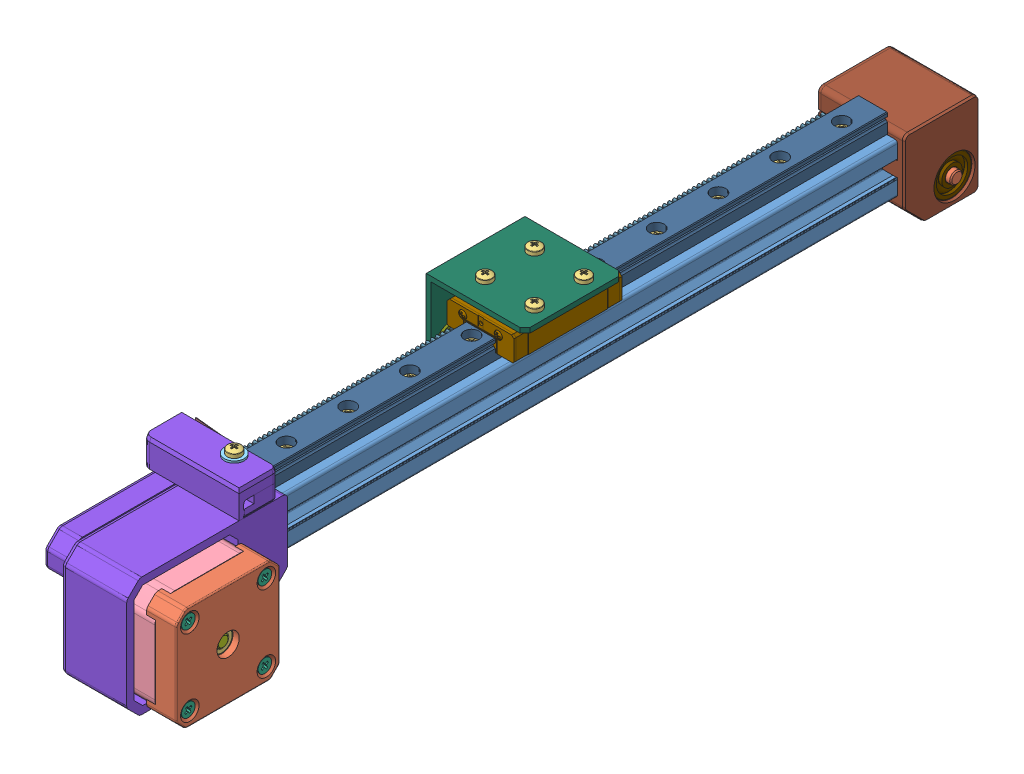
SolidWorks assembly Assem1, configuration По умолчанию. Lengths in mm.
Overall size (62 62.65 345.25).
71 component instances, 24 part files, 140 mates.
Components (placement in the parent):
- rsi_2020_274-1: rsi_2020_274 [По умолчанию] at origin size (20 20 274)
- 17HM15-0904S-1: 17HM15-0904S [По умолчанию] at (30 -11.15 303.15) x (0 0 -1) z (0 1 0) size (42.3 62 42.3)
  - nema17_bottom_40mm-1: nema17_bottom_40mm [По умолчанию] at origin size (42 12 42)
  - radial ball bearing_68_din-1: radial ball bearing_68_din [DIN 625 - 625 - 8,SI,NC,8_68] at (0 5 0) x (0 -1 0) z (0 0 1) size (5 16 16)
  - nema17_middle_40mm-1: nema17_middle_40mm [По умолчанию] at (0 8.5 0) size (42.3 23.5 42.3)
  - nema17_top_40mm-1: nema17_top_40mm [По умолчанию] at (0 32 0) size (42.3 12.6 42.3)
  - radial ball bearing_68_din-3: radial ball bearing_68_din [DIN 625 - 625 - 8,SI,NC,8_68] at (0 38.1 0) x (0 1 0) z (0 0 1) size (5 16 16)
  - countersunk flat head cross recess screw_din-1: countersunk flat head cross recess screw_din [ISO 7046-1 - M3 x 30 - Z --- 30N] at (15.5 0.6 15.5) x (0 1 0) z (0.546944 0 -0.837169) size (30 5.5 5.5)
  - countersunk flat head cross recess screw_din-2: countersunk flat head cross recess screw_din [ISO 7046-1 - M3 x 25 - Z --- 25N] at (15.5 0.6 -15.5) x (0 1 0) z (0.546944 0 -0.837169) size (25 5.5 5.5)
  - countersunk flat head cross recess screw_din-3: countersunk flat head cross recess screw_din [ISO 7046-1 - M3 x 30 - Z --- 30N] at (-15.5 0.6 15.5) x (0 1 0) z (0.546944 0 -0.837169) size (30 5.5 5.5)
  - countersunk flat head cross recess screw_din-4: countersunk flat head cross recess screw_din [ISO 7046-1 - M3 x 30 - Z --- 30N] at (-15.5 0.6 -15.5) x (0 1 0) z (0.546944 0 -0.837169) size (30 5.5 5.5)
  - nema17_shaft_40mm-1: nema17_shaft_40mm [По умолчанию] at (0 2 0) x (-0.412738 0 0.91085) z (-0.91085 0 -0.412738) size (5 60 5)
- nema17_mount_1-1: nema17_mount_1 [По умолчанию] at (-13 -10.7443 294.7873) x (0 0 -1) z (1 0 0) size (65.25 59.3 39.22)
- MGN12-H-1: MGN12-H [По умолчанию] at (0 18 148.9835) size (27 10 45.19)
- MGN12_250-1: MGN12_250 [По умолчанию] at (0 14 12) size (12 8 250)
- idle_pul_mount_1-1: idle_pul_mount_1 [По умолчанию] at (13 -3.403 -4.0666) x (0 0 1) z (-1 0 0) size (30 34 35)
- GT2_16T_13x14-1: GT2_16T_13x14 [Конфигурация1] at (-26.5 -11.15 303.15) x (1 0 0) z (0 0.386253 0.922393) size (14.1 13 13)
- GT2_16T_13x14-2: GT2_16T_13x14 [Конфигурация1] at (-26.5 -11.15 -8.1562) x (1 0 0) z (0 0.133178 -0.991092) size (14.1 13 13)
- SS-5GL_microswitch-2: SS-5GL_microswitch [Default] at (-42.2883 22.25 275.1397) x (0 -1 0) z (1 0 0) size (6.5 17.14 19.7)
- belt_250-1: belt_250 [По умолчанию] at (-19.83 -1.6143 147.7424) size (6 22.27 322.67)
- alum_40x40x2-1: alum_40x40x2 [По умолчанию] at (-21.9 23 168.9835) x (0 0 -1) z (0 -1 0) size (40 40 40)
- idle_pulley_16-1: idle_pulley_16 [По умолчанию] at (-16.4162 -0.75 136.4835) x (0 1 0) z (0 0 1) size (13 9 13)
- idle_pulley_16-2: idle_pulley_16 [По умолчанию] at (-16.4162 -0.75 161.4835) x (0 1 0) z (0 0 1) size (13 9 13)
- mgn12_fix-1: mgn12_fix [По умолчанию] at (0 12.9786 54.5) x (1 0 0) z (0 1 0) size (9.5 35 6)
- mgn12_fix-2: mgn12_fix [По умолчанию] at (0 12.9786 104.5) x (1 0 0) z (0 1 0) size (9.5 35 6)
- mgn12_fix-3: mgn12_fix [По умолчанию] at (0 12.9786 254.5) x (1 0 0) z (0 1 0) size (9.5 35 6)
- mgn12_fix-4: mgn12_fix [По умолчанию] at (0 12.9786 154.5) x (1 0 0) z (0 1 0) size (9.5 35 6)
- mgn12_fix-5: mgn12_fix [По умолчанию] at (0 12.9786 204.5) x (1 0 0) z (0 1 0) size (9.5 35 6)
- instrument ball bearing_68_am-1: instrument ball bearing_68_am [AFBMA 12.1.4.1 - 0050-16 - 8,SI,NC,8_68] at (-9.5 -11.15 -8.1562) size (5 16 16)
- instrument ball bearing_68_am-2: instrument ball bearing_68_am [AFBMA 12.1.4.1 - 0050-16 - 8,SI,NC,8_68] at (9.5 -11.15 -8.1562) size (5 16 16)
- socket head cap screw_am-1: socket head cap screw_am [B18.3.1M - 5 x 0.8 x 20 Hex SHCS -- 20NHX] at (0 0 280.85) x (0 0 -1) z (1 0 0) size (25 8.5 8.5)
- socket head cap screw_am-2: socket head cap screw_am [B18.3.1M - 5 x 0.8 x 20 Hex SHCS -- 20NHX] at (0 0 -11) x (0 0 1) z (-1 0 0) size (25 8.5 8.5)
- continous stud_am-1: continous stud_am [AM -- M5 x 45  N] at (-31 -11.15 -8.1562) size (45 5 5)
- pan head cross recess screw_din-1: pan head cross recess screw_din [ISO 7045 - M3 x 16 - Z --- 16N] at (-10 -0.75 161.4835) x (-1 0 0) z (0 0.924225 0.381849) size (18.35 5.6 5.6)
- pan head cross recess screw_din-2: pan head cross recess screw_din [ISO 7045 - M3 x 16 - Z --- 16N] at (-10 -0.75 136.4835) x (-1 0 0) z (0 0.924225 0.381849) size (18.35 5.6 5.6)
- prevailing torque nut style 1 insert_din-3: prevailing torque nut style 1 insert_din [DIN EN ISO 7040 - M3 - N] at (-26.05 -0.75 136.4835) x (0 0 1) z (-1 0 0) size (5.5 6.35 4.5)
- prevailing torque nut style 1 insert_din-4: prevailing torque nut style 1 insert_din [DIN EN ISO 7040 - M3 - N] at (-26.05 -0.75 161.4835) x (0 0 1) z (-1 0 0) size (5.5 6.35 4.5)
- plain washer 6902 type abc_din-1: plain washer 6902 type abc_din [DIN 6902-A3.2] at (-13 -26.65 318.65) x (-1 0 0) z (0 0.924225 0.381849) size (0.8 8 8)
- pan head cross recess screw_din-4: pan head cross recess screw_din [ISO 7045 - M3 x 6 - Z --- 6N] at (-16.2 -26.65 318.65) size (8.35 5.6 5.6)
- pan head cross recess screw_din-5: pan head cross recess screw_din [ISO 7045 - M3 x 6 - Z --- 6N] at (-16.2 -26.65 287.65) size (8.35 5.6 5.6)
- plain washer 6902 type abc_din-2: plain washer 6902 type abc_din [DIN 6902-A3.2] at (-13 -26.65 287.65) x (-1 0 0) z (0 0.924225 0.381849) size (0.8 8 8)
- pan head cross recess screw_din-6: pan head cross recess screw_din [ISO 7045 - M3 x 16 - Z --- 16N] at (-25.2 4.35 287.65) size (18.35 5.6 5.6)
- plain washer 6902 type abc_din-3: plain washer 6902 type abc_din [DIN 6902-A3.2] at (-22 4.35 287.65) x (-1 0 0) z (0 0.924225 0.381849) size (0.8 8 8)
- plain washer 6902 type abc_din-4: plain washer 6902 type abc_din [DIN 6902-A3.2] at (-22 4.35 318.65) x (-1 0 0) z (0 0.924225 0.381849) size (0.8 8 8)
- pan head cross recess screw_din-7: pan head cross recess screw_din [ISO 7045 - M3 x 20 - Z --- 20N] at (-25.2 4.35 318.65) size (22.35 5.6 5.6)
- pan head cross recess screw_din-9: pan head cross recess screw_din [ISO 7045 - M3 x 8 - Z --- 8N] at (0 15.9 24.5) x (0 -1 0) z (0 0 1) size (10.35 5.6 5.6)
- pan head cross recess screw_din-10: pan head cross recess screw_din [ISO 7045 - M3 x 8 - Z --- 8N] at (0 15.9 49.5) x (0 -1 0) z (-0.931961 0 -0.362559) size (10.35 5.6 5.6)
- hex nut style 1 gradeab_din-1: hex nut style 1 gradeab_din [Hexagon Nut ISO 4032 - M3 - D - N] at (0 5.1 24.5) x (0.5 0 0.866025) z (0 -1 0) size (5.5 6.35 2.4)
- hex nut style 1 gradeab_din-2: hex nut style 1 gradeab_din [Hexagon Nut ISO 4032 - M3 - D - N] at (0 5.1 49.5) x (0.5 0 0.866025) z (0 -1 0) size (5.5 6.35 2.4)
- hex nut style 1 gradeab_din-3: hex nut style 1 gradeab_din [Hexagon Nut ISO 4032 - M3 - D - N] at (0 5.1 99.5) x (0.5 0 0.866025) z (0 -1 0) size (5.5 6.35 2.4)
- hex nut style 1 gradeab_din-4: hex nut style 1 gradeab_din [Hexagon Nut ISO 4032 - M3 - D - N] at (0 5.1 74.5) x (0.5 0 0.866025) z (0 -1 0) size (5.5 6.35 2.4)
- pan head cross recess screw_din-11: pan head cross recess screw_din [ISO 7045 - M3 x 8 - Z --- 8N] at (0 15.9 74.5) x (0 -1 0) z (0 0 1) size (10.35 5.6 5.6)
- pan head cross recess screw_din-12: pan head cross recess screw_din [ISO 7045 - M3 x 8 - Z --- 8N] at (0 15.9 99.5) x (0 -1 0) z (-0.931961 0 -0.362559) size (10.35 5.6 5.6)
- hex nut style 1 gradeab_din-5: hex nut style 1 gradeab_din [Hexagon Nut ISO 4032 - M3 - D - N] at (0 5.1 249.5) x (0.5 0 0.866025) z (0 -1 0) size (5.5 6.35 2.4)
- hex nut style 1 gradeab_din-6: hex nut style 1 gradeab_din [Hexagon Nut ISO 4032 - M3 - D - N] at (0 5.1 224.5) x (0.5 0 0.866025) z (0 -1 0) size (5.5 6.35 2.4)
- pan head cross recess screw_din-13: pan head cross recess screw_din [ISO 7045 - M3 x 8 - Z --- 8N] at (0 15.9 224.5) x (0 -1 0) z (0 0 1) size (10.35 5.6 5.6)
- pan head cross recess screw_din-14: pan head cross recess screw_din [ISO 7045 - M3 x 8 - Z --- 8N] at (0 15.9 249.5) x (0 -1 0) z (-0.931961 0 -0.362559) size (10.35 5.6 5.6)
- hex nut style 1 gradeab_din-7: hex nut style 1 gradeab_din [Hexagon Nut ISO 4032 - M3 - D - N] at (0 5.1 149.5) x (0.5 0 0.866025) z (0 -1 0) size (5.5 6.35 2.4)
- hex nut style 1 gradeab_din-8: hex nut style 1 gradeab_din [Hexagon Nut ISO 4032 - M3 - D - N] at (0 5.1 124.5) x (0.5 0 0.866025) z (0 -1 0) size (5.5 6.35 2.4)
- pan head cross recess screw_din-15: pan head cross recess screw_din [ISO 7045 - M3 x 8 - Z --- 8N] at (0 15.9 124.5) x (0 -1 0) z (0 0 1) size (10.35 5.6 5.6)
- pan head cross recess screw_din-16: pan head cross recess screw_din [ISO 7045 - M3 x 8 - Z --- 8N] at (0 15.9 149.5) x (0 -1 0) z (-0.931961 0 -0.362559) size (10.35 5.6 5.6)
- hex nut style 1 gradeab_din-9: hex nut style 1 gradeab_din [Hexagon Nut ISO 4032 - M3 - D - N] at (0 5.1 199.5) x (0.5 0 0.866025) z (0 -1 0) size (5.5 6.35 2.4)
- hex nut style 1 gradeab_din-10: hex nut style 1 gradeab_din [Hexagon Nut ISO 4032 - M3 - D - N] at (0 5.1 174.5) x (0.5 0 0.866025) z (0 -1 0) size (5.5 6.35 2.4)
- pan head cross recess screw_din-17: pan head cross recess screw_din [ISO 7045 - M3 x 8 - Z --- 8N] at (0 15.9 174.5) x (0 -1 0) z (0 0 1) size (10.35 5.6 5.6)
- pan head cross recess screw_din-18: pan head cross recess screw_din [ISO 7045 - M3 x 8 - Z --- 8N] at (0 15.9 199.5) x (0 -1 0) z (-0.931961 0 -0.362559) size (10.35 5.6 5.6)
- pan head cross recess screw_din-19: pan head cross recess screw_din [ISO 7045 - M3 x 6 - Z --- 6N] at (-10 27.4 158.9835) x (0 -1 0) z (0 0 1) size (8.35 5.6 5.6)
- pan head cross recess screw_din-20: pan head cross recess screw_din [ISO 7045 - M3 x 6 - Z --- 6N] at (-10 27.4 138.9835) x (0 -1 0) z (0 0 1) size (8.35 5.6 5.6)
- pan head cross recess screw_din-21: pan head cross recess screw_din [ISO 7045 - M3 x 6 - Z --- 6N] at (10 27.4 138.9835) x (0 -1 0) z (0 0 1) size (8.35 5.6 5.6)
- pan head cross recess screw_din-22: pan head cross recess screw_din [ISO 7045 - M3 x 6 - Z --- 6N] at (10 27.4 158.9835) x (0 -1 0) z (0 0 1) size (8.35 5.6 5.6)
- plain washer 6902 type abc_din-5: plain washer 6902 type abc_din [DIN 6902-A3.2] at (0 24 270.6521) x (0 1 0) z (0.924225 0 0.381849) size (0.8 8 8)
- pan head cross recess screw_din-23: pan head cross recess screw_din [ISO 7045 - M3 x 16 - Z --- 16N] at (0 27.2 270.6521) x (0 -1 0) z (0 0 1) size (18.35 5.6 5.6)
Mates (geometry in assembly coordinates):
- Concentric1: concentric aligned: cylinder of rsi_2020_274-1 through (0 0 274) axis (0 0 -1) radius 2.5; cylinder of nema17_mount_1-1 through (0 0 327.251) axis (0 0 -1) radius 3.1
- Coincident4: coincident anti-aligned: plane of rsi_2020_274-1 through (0 0 274) normal (0 0 1); plane of nema17_mount_1-1 through (-13 -10.7443 274) normal (0 0 -1)
- Parallel2: parallel aligned: plane of rsi_2020_274-1 through (10 0 274) normal (1 0 0); plane of nema17_mount_1-1 through (13 -10.7443 294.7873) normal (1 0 0)
- Concentric2: concentric anti-aligned: cylinder of 17HM15-0904S-1/nema17_top_40mm-1 through (-12 -11.15 303.15) axis (1 0 0) radius 11; cylinder of nema17_mount_1-1 through (-10 -11.15 303.15) axis (-1 0 0) radius 11.05
- Coincident6: coincident anti-aligned: plane of 17HM15-0904S-1/nema17_top_40mm-1 through (-10 -11.15 303.15) normal (-1 0 0); plane of nema17_mount_1-1 through (-10 -10.7443 294.7873) normal (1 0 0)
- Parallel3: parallel aligned: plane of 17HM15-0904S-1/nema17_middle_40mm-1 through (-2 10 317.5735) normal (0 1 0); plane of nema17_mount_1-1 through (13 13 294.7873) normal (0 1 0)
- Coincident8: coincident anti-aligned: plane of MGN12-H-1 through (6 18 165.1835) normal (-1 0 0); plane of MGN12_250-1 through (6 10.3 262) normal (1 0 0)
- Coincident9: coincident anti-aligned: plane of MGN12-H-1 through (0 18 165.1835) normal (0 -1 0); plane of MGN12_250-1 through (-5.7 18 262) normal (0 1 0)
- Coincident10: coincident anti-aligned: plane of rsi_2020_274-1 through (0 10 274) normal (0 1 0); plane of MGN12_250-1 through (-5.7 10 262) normal (0 -1 0)
- Coincident11: coincident anti-aligned: plane of nema17_mount_1-1 through (13 -10.7443 262) normal (0 0 -1); plane of MGN12_250-1 through (6.3091 15.5 262) normal (0 0 1)
- Distance2: distance = 4 mm aligned: plane of MGN12_250-1 through (-6 10.3 262) normal (-1 0 0); plane of rsi_2020_274-1 through (-10 0 274) normal (-1 0 0)
- Concentric5: concentric anti-aligned: cylinder of rsi_2020_274-1 through (0 0 274) axis (0 0 -1) radius 2.5; cylinder of idle_pul_mount_1-1 through (0 0 -18.001) axis (0 0 1) radius 3.1
- Coincident14: coincident anti-aligned: plane of rsi_2020_274-1 through (0 0 0) normal (0 0 -1); plane of idle_pul_mount_1-1 through (13 -3.403 0) normal (0 0 1)
- Concentric6: concentric aligned: cylinder of 17HM15-0904S-1/nema17_shaft_40mm-1 through (-32 -11.15 303.15) axis (1 0 0) radius 2.5; cylinder of GT2_16T_13x14-1 through (-26.5 -11.15 303.15) axis (1 0 0) radius 2.5
- Coincident15: coincident anti-aligned: plane of idle_pul_mount_1-1 through (-7 -11.15 -8.1562) normal (-1 0 0); plane of instrument ball bearing_68_am-1 through (-7 -3.45 -8.1562) normal (1 0 0)
- Concentric7: concentric anti-aligned: cylinder of idle_pul_mount_1-1 through (-7 -11.15 -8.1562) axis (-1 0 0) radius 8; cylinder of instrument ball bearing_68_am-1 through (-30.1375 -11.15 -8.1562) axis (1 0 0) radius 8
- Coincident16: coincident aligned: circle of idle_pul_mount_1-1; plane of instrument ball bearing_68_am-2 through (7 -4.8 -8.1562) normal (-1 0 0)
- Concentric8: concentric aligned: cylinder of idle_pul_mount_1-1 through (7 -11.15 -8.1562) axis (1 0 0) radius 8; cylinder of instrument ball bearing_68_am-2 through (-11.1375 -11.15 -8.1562) axis (1 0 0) radius 8
- Concentric9: concentric anti-aligned: cylinder of idle_pul_mount_1-1 through (0 0 -18.001) axis (0 0 1) radius 3.1; cylinder of socket head cap screw_am-2 through (0 0 -42.75) axis (0 0 -1) radius 4.25
- Coincident17: coincident anti-aligned: plane of idle_pul_mount_1-1 through (0 0 -6) normal (0 0 -1); plane of socket head cap screw_am-2 through (0 4.25 -6) normal (0 0 1)
- Concentric10: concentric anti-aligned: cylinder of nema17_mount_1-1 through (0 0 327.251) axis (0 0 -1) radius 3.1; cylinder of socket head cap screw_am-1 through (0 0 312.6) axis (0 0 1) radius 2.5
- Coincident18: coincident anti-aligned: plane of nema17_mount_1-1 through (0 0 275.85) normal (0 0 1); plane of socket head cap screw_am-1 through (0 4.25 275.85) normal (0 0 -1)
- Concentric11: concentric anti-aligned: cylinder of instrument ball bearing_68_am-1 through (-30.1375 -11.15 -8.1562) axis (1 0 0) radius 2.5; cylinder of continous stud_am-1 through (-34.175 -11.15 -8.1562) axis (-1 0 0) radius 2.5
- Distance3: distance = 2 mm aligned: plane of continous stud_am-1 through (14 -8.65 -8.1562) normal (1 0 0); plane of instrument ball bearing_68_am-2 through (12 -8.35 -8.1562) normal (1 0 0)
- Concentric12: concentric anti-aligned: cylinder of continous stud_am-1 through (-34.175 -11.15 -8.1562) axis (-1 0 0) radius 2.5; cylinder of GT2_16T_13x14-2 through (-26.5 -11.15 -8.1562) axis (1 0 0) radius 2.5
- Coincident20: coincident aligned: plane of nema17_mount_1-1 through (13 13 294.7873) normal (0 1 0); plane of idle_pul_mount_1-1 through (-13 13 -4.0666) normal (0 1 0)
- Coincident21: coincident aligned: plane of GT2_16T_13x14-1 through (-26.5 -11.15 303.15) normal (-1 0 0); plane of GT2_16T_13x14-2 through (-26.5 -11.15 -8.1562) normal (-1 0 0)
- Distance4: distance = 0.5 mm anti-aligned: plane of GT2_16T_13x14-2 through (-20.33 -11.15 -8.1562) normal (1 0 0); plane of belt_250-1 through (-19.83 -5.8558 5.1368) normal (-1 0 0)
- Coincident23: coincident anti-aligned: plane of MGN12-H-1 through (0 23 165.1835) normal (0 1 0); plane of alum_40x40x2-1 through (-21.9 23 128.9835) normal (0 -1 0)
- Concentric13: concentric anti-aligned: cylinder of alum_40x40x2-1 through (16.101 -0.75 136.4835) axis (-1 0 0) radius 1.5; cylinder of idle_pulley_16-1 through (-16.4162 -0.75 136.4835) axis (1 0 0) radius 1.5
- Concentric14: concentric anti-aligned: cylinder of alum_40x40x2-1 through (16.101 -0.75 161.4835) axis (-1 0 0) radius 1.5; cylinder of idle_pulley_16-2 through (-16.4162 -0.75 161.4835) axis (1 0 0) radius 1.5
- Distance6: distance = 0.5 mm anti-aligned: plane of idle_pulley_16-1 through (-21.4 -0.75 134.9835) normal (-1 0 0); plane of alum_40x40x2-1 through (-21.9 -15 128.9835) normal (1 0 0)
- Distance7: distance = 0.5 mm anti-aligned: plane of idle_pulley_16-2 through (-21.4 -0.75 159.9835) normal (-1 0 0); plane of alum_40x40x2-1 through (-21.9 -15 128.9835) normal (1 0 0)
- Concentric15: concentric aligned: cylinder of idle_pulley_16-2 through (-16.4162 -0.75 161.4835) axis (1 0 0) radius 1.5; cylinder of pan head cross recess screw_din-1 through (15.4 -0.75 161.4835) axis (1 0 0) radius 2.8
- Coincident28: coincident anti-aligned: plane of idle_pulley_16-2 through (-12.4 -0.75 154.9835) normal (1 0 0); plane of pan head cross recess screw_din-1 through (-12.4 -1.3228 162.8699) normal (-1 0 0)
- Concentric16: concentric aligned: cylinder of idle_pulley_16-1 through (-16.4162 -0.75 136.4835) axis (1 0 0) radius 1.5; cylinder of pan head cross recess screw_din-2 through (15.4 -0.75 136.4835) axis (1 0 0) radius 2.8
- Coincident29: coincident anti-aligned: plane of idle_pulley_16-1 through (-12.4 -0.75 129.9835) normal (1 0 0); plane of pan head cross recess screw_din-2 through (-12.4 -1.3228 137.8699) normal (-1 0 0)
- Concentric20: concentric aligned: cylinder of MGN12-H-1 through (-10 17.15 158.9835) axis (0 1 0) radius 1.5; cylinder of alum_40x40x2-1 through (-10 -15.001 158.9835) axis (0 1 0) radius 1.5
- Concentric21: concentric aligned: cylinder of MGN12-H-1 through (10 17.15 138.9835) axis (0 1 0) radius 1.5; cylinder of alum_40x40x2-1 through (10 -15.001 138.9835) axis (0 1 0) radius 1.5
- Concentric29: concentric anti-aligned: cylinder of pan head cross recess screw_din-2 through (15.4 -0.75 136.4835) axis (1 0 0) radius 1.5; cylinder of prevailing torque nut style 1 insert_din-3 through (-23.9 -0.75 136.4835) axis (-1 0 0) radius 1.25
- Concentric30: concentric anti-aligned: cylinder of pan head cross recess screw_din-1 through (15.4 -0.75 161.4835) axis (1 0 0) radius 1.5; cylinder of prevailing torque nut style 1 insert_din-4 through (-23.9 -0.75 161.4835) axis (-1 0 0) radius 1.25
- Coincident36: coincident anti-aligned: plane of alum_40x40x2-1 through (-23.9 25 128.9835) normal (-1 0 0); plane of prevailing torque nut style 1 insert_din-3 through (-23.9 -0.75 130.9835) normal (1 0 0)
- Coincident37: coincident anti-aligned: plane of alum_40x40x2-1 through (-23.9 25 128.9835) normal (-1 0 0); plane of prevailing torque nut style 1 insert_din-4 through (-23.9 -0.75 155.9835) normal (1 0 0)
- Concentric32: concentric anti-aligned: cylinder of nema17_mount_1-1 through (-10 -26.65 318.65) axis (-1 0 0) radius 1.6; cylinder of plain washer 6902 type abc_din-1 through (-13.8 -26.65 318.65) axis (1 0 0) radius 1.6
- Coincident39: coincident anti-aligned: plane of nema17_mount_1-1 through (-13 -10.7443 294.7873) normal (-1 0 0); plane of plain washer 6902 type abc_din-1 through (-13 -26.65 318.65) normal (1 0 0)
- Coincident40: coincident anti-aligned: plane of plain washer 6902 type abc_din-1 through (-13.8 -26.65 318.65) normal (-1 0 0); plane of pan head cross recess screw_din-4 through (-13.8 -25.15 318.65) normal (1 0 0)
- Concentric41: concentric anti-aligned: cylinder of plain washer 6902 type abc_din-1 through (-13.8 -26.65 318.65) axis (1 0 0) radius 1.6; cylinder of pan head cross recess screw_din-4 through (-41.6 -26.65 318.65) axis (-1 0 0) radius 1.5
- Coincident47: coincident anti-aligned: plane of pan head cross recess screw_din-5 through (-13.8 -25.15 287.65) normal (1 0 0); plane of plain washer 6902 type abc_din-2 through (-13.8 -26.65 287.65) normal (-1 0 0)
- Concentric42: concentric anti-aligned: cylinder of pan head cross recess screw_din-5 through (-41.6 -26.65 287.65) axis (-1 0 0) radius 1.5; cylinder of plain washer 6902 type abc_din-2 through (-13.8 -26.65 287.65) axis (1 0 0) radius 1.6
- Concentric43: concentric anti-aligned: cylinder of nema17_mount_1-1 through (-10 -26.65 287.65) axis (-1 0 0) radius 1.6; cylinder of plain washer 6902 type abc_din-2 through (-13.8 -26.65 287.65) axis (1 0 0) radius 1.6
- Coincident48: coincident anti-aligned: plane of nema17_mount_1-1 through (-13 -10.7443 294.7873) normal (-1 0 0); plane of plain washer 6902 type abc_din-2 through (-13 -26.65 287.65) normal (1 0 0)
- Coincident49: coincident anti-aligned: plane of pan head cross recess screw_din-6 through (-22.8 5.85 287.65) normal (1 0 0); plane of plain washer 6902 type abc_din-3 through (-22.8 4.35 287.65) normal (-1 0 0)
- Concentric44: concentric anti-aligned: cylinder of pan head cross recess screw_din-6 through (-50.6 4.35 287.65) axis (-1 0 0) radius 1.5; cylinder of plain washer 6902 type abc_din-3 through (-22.8 4.35 287.65) axis (1 0 0) radius 1.6
- Concentric45: concentric anti-aligned: cylinder of nema17_mount_1-1 through (-10 4.35 287.65) axis (-1 0 0) radius 1.6; cylinder of plain washer 6902 type abc_din-3 through (-22.8 4.35 287.65) axis (1 0 0) radius 1.6
- Coincident50: coincident anti-aligned: plane of nema17_mount_1-1 through (-22 2 264) normal (-1 0 0); plane of plain washer 6902 type abc_din-3 through (-22 4.35 287.65) normal (1 0 0)
- Coincident51: coincident anti-aligned: plane of plain washer 6902 type abc_din-4 through (-22.8 4.35 318.65) normal (-1 0 0); plane of pan head cross recess screw_din-7 through (-22.8 5.85 318.65) normal (1 0 0)
- Concentric46: concentric anti-aligned: cylinder of plain washer 6902 type abc_din-4 through (-22.8 4.35 318.65) axis (1 0 0) radius 1.6; cylinder of pan head cross recess screw_din-7 through (-50.6 4.35 318.65) axis (-1 0 0) radius 1.5
- Concentric47: concentric anti-aligned: cylinder of nema17_mount_1-1 through (-10 4.35 318.65) axis (-1 0 0) radius 1.6; cylinder of plain washer 6902 type abc_din-4 through (-22.8 4.35 318.65) axis (1 0 0) radius 1.6
- Coincident52: coincident anti-aligned: plane of nema17_mount_1-1 through (-22 2 264) normal (-1 0 0); plane of plain washer 6902 type abc_din-4 through (-22 4.35 318.65) normal (1 0 0)
- Distance9: distance = 5.5 mm aligned: plane of GT2_16T_13x14-1 through (-26.5 -11.15 303.15) normal (-1 0 0); plane of 17HM15-0904S-1/nema17_shaft_40mm-1 through (-32 -11.15 303.15) normal (-1 0 0)
- Concentric50: concentric anti-aligned: cylinder of MGN12_250-1 through (0 10 24.5) axis (0 1 0) radius 1.75; cylinder of mgn12_fix-1 through (0 10.001 24.5) axis (0 -1 0) radius 1.6
- Concentric51: concentric anti-aligned: cylinder of MGN12_250-1 through (0 10 49.5) axis (0 1 0) radius 1.75; cylinder of mgn12_fix-1 through (0 10.001 49.5) axis (0 -1 0) radius 1.6
- Coincident55: coincident anti-aligned: plane of MGN12_250-1 through (-5.7 10 262) normal (0 -1 0); plane of mgn12_fix-1 through (-3 10 19.5) normal (0 1 0)
- Concentric54: concentric aligned: cylinder of MGN12_250-1 through (0 10 49.5) axis (0 1 0) radius 1.75; cylinder of pan head cross recess screw_din-10 through (0 41.3 49.5) axis (0 1 0) radius 2.8
- Coincident57: coincident anti-aligned: plane of MGN12_250-1 through (0 13.5 49.5) normal (0 1 0); plane of pan head cross recess screw_din-10 through (-0.5438 13.5 50.8979) normal (0 -1 0)
- Parallel6: parallel aligned: plane of mgn12_fix-1 through (-2.9 7.5 22.8257) normal (0.5 0 0.866025); plane of hex nut style 1 gradeab_din-1 through (0 7.5 27.6754) normal (0.5 0 0.866025)
- Coincident61: coincident anti-aligned: plane of mgn12_fix-1 through (0 7.5 54.5) normal (0 -1 0); plane of hex nut style 1 gradeab_din-1 through (-2.75 7.5 26.0877) normal (0 1 0)
- Concentric57: concentric anti-aligned: cylinder of pan head cross recess screw_din-10 through (0 41.3 49.5) axis (0 1 0) radius 1.5; cylinder of hex nut style 1 gradeab_din-2 through (0 7.5 49.5) axis (0 -1 0) radius 1.25
- Parallel7: parallel aligned: plane of mgn12_fix-1 through (0 7.5 46.1514) normal (0.5 0 0.866025); plane of hex nut style 1 gradeab_din-2 through (0 7.5 52.6754) normal (0.5 0 0.866025)
- Coincident62: coincident anti-aligned: plane of mgn12_fix-1 through (0 7.5 54.5) normal (0 -1 0); plane of hex nut style 1 gradeab_din-2 through (-2.75 7.5 51.0877) normal (0 1 0)
- Concentric59: concentric aligned: cylinder of MGN12_250-1 through (0 10 24.5) axis (0 1 0) radius 1.75; cylinder of pan head cross recess screw_din-9 through (0 41.3 24.5) axis (0 1 0) radius 1.5
- Coincident64: coincident anti-aligned: plane of MGN12_250-1 through (0 13.5 24.5) normal (0 1 0); plane of pan head cross recess screw_din-9 through (1.5 13.5 24.5) normal (0 -1 0)
- Concentric85: concentric anti-aligned: cylinder of pan head cross recess screw_din-9 through (0 41.3 24.5) axis (0 1 0) radius 1.5; cylinder of hex nut style 1 gradeab_din-1 through (0 7.5 24.5) axis (0 -1 0) radius 1.25
- Parallel16: parallel aligned: plane of mgn12_fix-2 through (-2.9 7.5 72.8257) normal (0.5 0 0.866025); plane of hex nut style 1 gradeab_din-4 through (0 7.5 77.6754) normal (0.5 0 0.866025)
- Coincident85: coincident anti-aligned: plane of mgn12_fix-2 through (0 7.5 104.5) normal (0 -1 0); plane of hex nut style 1 gradeab_din-4 through (-2.75 7.5 76.0877) normal (0 1 0)
- Concentric86: concentric anti-aligned: cylinder of hex nut style 1 gradeab_din-3 through (0 7.5 99.5) axis (0 -1 0) radius 1.25; cylinder of pan head cross recess screw_din-12 through (0 41.3 99.5) axis (0 1 0) radius 1.5
- Parallel17: parallel aligned: plane of mgn12_fix-2 through (0 7.5 96.1514) normal (0.5 0 0.866025); plane of hex nut style 1 gradeab_din-3 through (0 7.5 102.6754) normal (0.5 0 0.866025)
- Coincident86: coincident anti-aligned: plane of mgn12_fix-2 through (0 7.5 104.5) normal (0 -1 0); plane of hex nut style 1 gradeab_din-3 through (-2.75 7.5 101.0877) normal (0 1 0)
- Concentric87: concentric anti-aligned: cylinder of hex nut style 1 gradeab_din-4 through (0 7.5 74.5) axis (0 -1 0) radius 1.25; cylinder of pan head cross recess screw_din-11 through (0 41.3 74.5) axis (0 1 0) radius 1.5
- Concentric88: concentric anti-aligned: cylinder of MGN12_250-1 through (0 10 74.5) axis (0 1 0) radius 1.75; cylinder of mgn12_fix-2 through (0 10.001 74.5) axis (0 -1 0) radius 1.6
- Concentric89: concentric anti-aligned: cylinder of MGN12_250-1 through (0 10 99.5) axis (0 1 0) radius 1.75; cylinder of mgn12_fix-2 through (0 10.001 99.5) axis (0 -1 0) radius 1.6
- Coincident87: coincident anti-aligned: plane of MGN12_250-1 through (-5.7 10 262) normal (0 -1 0); plane of mgn12_fix-2 through (-3 10 69.5) normal (0 1 0)
- Concentric90: concentric aligned: cylinder of MGN12_250-1 through (0 10 99.5) axis (0 1 0) radius 1.75; cylinder of pan head cross recess screw_din-12 through (0 41.3 99.5) axis (0 1 0) radius 2.8
- Coincident88: coincident anti-aligned: plane of MGN12_250-1 through (0 13.5 49.5) normal (0 1 0); plane of pan head cross recess screw_din-12 through (-0.5438 13.5 100.8979) normal (0 -1 0)
- Concentric91: concentric aligned: cylinder of MGN12_250-1 through (0 10 74.5) axis (0 1 0) radius 1.75; cylinder of pan head cross recess screw_din-11 through (0 41.3 74.5) axis (0 1 0) radius 1.5
- Coincident89: coincident anti-aligned: plane of MGN12_250-1 through (0 13.5 24.5) normal (0 1 0); plane of pan head cross recess screw_din-11 through (1.5 13.5 74.5) normal (0 -1 0)
- Parallel18: parallel aligned: plane of mgn12_fix-3 through (-2.9 7.5 222.8257) normal (0.5 0 0.866025); plane of hex nut style 1 gradeab_din-6 through (0 7.5 227.6754) normal (0.5 0 0.866025)
- Coincident90: coincident anti-aligned: plane of mgn12_fix-3 through (0 7.5 254.5) normal (0 -1 0); plane of hex nut style 1 gradeab_din-6 through (-2.75 7.5 226.0877) normal (0 1 0)
- Concentric92: concentric anti-aligned: cylinder of hex nut style 1 gradeab_din-5 through (0 7.5 249.5) axis (0 -1 0) radius 1.25; cylinder of pan head cross recess screw_din-14 through (0 41.3 249.5) axis (0 1 0) radius 1.5
- Parallel19: parallel aligned: plane of mgn12_fix-3 through (0 7.5 246.1514) normal (0.5 0 0.866025); plane of hex nut style 1 gradeab_din-5 through (0 7.5 252.6754) normal (0.5 0 0.866025)
- Coincident91: coincident anti-aligned: plane of mgn12_fix-3 through (0 7.5 254.5) normal (0 -1 0); plane of hex nut style 1 gradeab_din-5 through (-2.75 7.5 251.0877) normal (0 1 0)
- Concentric93: concentric anti-aligned: cylinder of hex nut style 1 gradeab_din-6 through (0 7.5 224.5) axis (0 -1 0) radius 1.25; cylinder of pan head cross recess screw_din-13 through (0 41.3 224.5) axis (0 1 0) radius 1.5
- Concentric94: concentric anti-aligned: cylinder of MGN12_250-1 through (0 10 224.5) axis (0 1 0) radius 1.75; cylinder of mgn12_fix-3 through (0 10.001 224.5) axis (0 -1 0) radius 1.6
- Coincident92: coincident anti-aligned: plane of MGN12_250-1 through (-5.7 10 262) normal (0 -1 0); plane of mgn12_fix-3 through (-3 10 219.5) normal (0 1 0)
- Coincident93: coincident anti-aligned: plane of MGN12_250-1 through (0 13.5 49.5) normal (0 1 0); plane of pan head cross recess screw_din-14 through (-0.5438 13.5 250.8979) normal (0 -1 0)
- Coincident94: coincident anti-aligned: plane of MGN12_250-1 through (0 13.5 24.5) normal (0 1 0); plane of pan head cross recess screw_din-13 through (1.5 13.5 224.5) normal (0 -1 0)
- Concentric95: concentric anti-aligned: cylinder of MGN12_250-1 through (0 10 249.5) axis (0 1 0) radius 1.75; cylinder of mgn12_fix-3 through (0 10.001 249.5) axis (0 -1 0) radius 1.6
- Concentric96: concentric aligned: cylinder of MGN12_250-1 through (0 10 249.5) axis (0 1 0) radius 1.75; cylinder of pan head cross recess screw_din-14 through (0 41.3 249.5) axis (0 1 0) radius 2.8
- Concentric97: concentric aligned: cylinder of MGN12_250-1 through (0 10 224.5) axis (0 1 0) radius 1.75; cylinder of pan head cross recess screw_din-13 through (0 41.3 224.5) axis (0 1 0) radius 1.5
- Parallel20: parallel aligned: plane of mgn12_fix-4 through (-2.9 7.5 122.8257) normal (0.5 0 0.866025); plane of hex nut style 1 gradeab_din-8 through (0 7.5 127.6754) normal (0.5 0 0.866025)
- Coincident95: coincident anti-aligned: plane of mgn12_fix-4 through (0 7.5 154.5) normal (0 -1 0); plane of hex nut style 1 gradeab_din-8 through (-2.75 7.5 126.0877) normal (0 1 0)
- Concentric98: concentric anti-aligned: cylinder of hex nut style 1 gradeab_din-7 through (0 7.5 149.5) axis (0 -1 0) radius 1.25; cylinder of pan head cross recess screw_din-16 through (0 41.3 149.5) axis (0 1 0) radius 1.5
- Parallel21: parallel aligned: plane of mgn12_fix-4 through (0 7.5 146.1514) normal (0.5 0 0.866025); plane of hex nut style 1 gradeab_din-7 through (0 7.5 152.6754) normal (0.5 0 0.866025)
- Coincident96: coincident anti-aligned: plane of mgn12_fix-4 through (0 7.5 154.5) normal (0 -1 0); plane of hex nut style 1 gradeab_din-7 through (-2.75 7.5 151.0877) normal (0 1 0)
- Concentric99: concentric anti-aligned: cylinder of hex nut style 1 gradeab_din-8 through (0 7.5 124.5) axis (0 -1 0) radius 1.25; cylinder of pan head cross recess screw_din-15 through (0 41.3 124.5) axis (0 1 0) radius 1.5
- Concentric100: concentric anti-aligned: cylinder of MGN12_250-1 through (0 10 124.5) axis (0 1 0) radius 1.75; cylinder of mgn12_fix-4 through (0 10.001 124.5) axis (0 -1 0) radius 1.6
- Coincident97: coincident anti-aligned: plane of MGN12_250-1 through (-5.7 10 262) normal (0 -1 0); plane of mgn12_fix-4 through (-3 10 119.5) normal (0 1 0)
- Coincident98: coincident anti-aligned: plane of MGN12_250-1 through (0 13.5 49.5) normal (0 1 0); plane of pan head cross recess screw_din-16 through (-0.5438 13.5 150.8979) normal (0 -1 0)
- Coincident99: coincident anti-aligned: plane of MGN12_250-1 through (0 13.5 24.5) normal (0 1 0); plane of pan head cross recess screw_din-15 through (1.5 13.5 124.5) normal (0 -1 0)
- Concentric101: concentric anti-aligned: cylinder of MGN12_250-1 through (0 10 149.5) axis (0 1 0) radius 1.75; cylinder of mgn12_fix-4 through (0 10.001 149.5) axis (0 -1 0) radius 1.6
- Concentric102: concentric aligned: cylinder of MGN12_250-1 through (0 10 149.5) axis (0 1 0) radius 1.75; cylinder of pan head cross recess screw_din-16 through (0 41.3 149.5) axis (0 1 0) radius 2.8
- Concentric103: concentric aligned: cylinder of MGN12_250-1 through (0 10 124.5) axis (0 1 0) radius 1.75; cylinder of pan head cross recess screw_din-15 through (0 41.3 124.5) axis (0 1 0) radius 1.5
- Parallel22: parallel aligned: plane of mgn12_fix-5 through (-2.9 7.5 172.8257) normal (0.5 0 0.866025); plane of hex nut style 1 gradeab_din-10 through (0 7.5 177.6754) normal (0.5 0 0.866025)
- Coincident100: coincident anti-aligned: plane of mgn12_fix-5 through (0 7.5 204.5) normal (0 -1 0); plane of hex nut style 1 gradeab_din-10 through (-2.75 7.5 176.0877) normal (0 1 0)
- Concentric104: concentric anti-aligned: cylinder of hex nut style 1 gradeab_din-9 through (0 7.5 199.5) axis (0 -1 0) radius 1.25; cylinder of pan head cross recess screw_din-18 through (0 41.3 199.5) axis (0 1 0) radius 1.5
- Parallel23: parallel aligned: plane of mgn12_fix-5 through (0 7.5 196.1514) normal (0.5 0 0.866025); plane of hex nut style 1 gradeab_din-9 through (0 7.5 202.6754) normal (0.5 0 0.866025)
- Coincident101: coincident anti-aligned: plane of mgn12_fix-5 through (0 7.5 204.5) normal (0 -1 0); plane of hex nut style 1 gradeab_din-9 through (-2.75 7.5 201.0877) normal (0 1 0)
- Concentric105: concentric anti-aligned: cylinder of hex nut style 1 gradeab_din-10 through (0 7.5 174.5) axis (0 -1 0) radius 1.25; cylinder of pan head cross recess screw_din-17 through (0 41.3 174.5) axis (0 1 0) radius 1.5
- Concentric106: concentric anti-aligned: cylinder of MGN12_250-1 through (0 10 174.5) axis (0 1 0) radius 1.75; cylinder of mgn12_fix-5 through (0 10.001 174.5) axis (0 -1 0) radius 1.6
- Coincident102: coincident anti-aligned: plane of MGN12_250-1 through (-5.7 10 262) normal (0 -1 0); plane of mgn12_fix-5 through (-3 10 169.5) normal (0 1 0)
- Coincident103: coincident anti-aligned: plane of MGN12_250-1 through (0 13.5 49.5) normal (0 1 0); plane of pan head cross recess screw_din-18 through (-0.5438 13.5 200.8979) normal (0 -1 0)
- Coincident104: coincident anti-aligned: plane of MGN12_250-1 through (0 13.5 24.5) normal (0 1 0); plane of pan head cross recess screw_din-17 through (1.5 13.5 174.5) normal (0 -1 0)
- Concentric107: concentric anti-aligned: cylinder of MGN12_250-1 through (0 10 199.5) axis (0 1 0) radius 1.75; cylinder of mgn12_fix-5 through (0 10.001 199.5) axis (0 -1 0) radius 1.6
- Concentric108: concentric aligned: cylinder of MGN12_250-1 through (0 10 199.5) axis (0 1 0) radius 1.75; cylinder of pan head cross recess screw_din-18 through (0 41.3 199.5) axis (0 1 0) radius 2.8
- Concentric109: concentric aligned: cylinder of MGN12_250-1 through (0 10 174.5) axis (0 1 0) radius 1.75; cylinder of pan head cross recess screw_din-17 through (0 41.3 174.5) axis (0 1 0) radius 1.5
- Concentric110: concentric aligned: cylinder of alum_40x40x2-1 through (-10 -15.001 158.9835) axis (0 1 0) radius 1.5; cylinder of pan head cross recess screw_din-19 through (-10 52.8 158.9835) axis (0 1 0) radius 2.8
- Coincident105: coincident anti-aligned: plane of alum_40x40x2-1 through (16.1 25 128.9835) normal (0 1 0); plane of pan head cross recess screw_din-19 through (-8.5 25 158.9835) normal (0 -1 0)
- Concentric111: concentric aligned: cylinder of alum_40x40x2-1 through (-10 -15.001 138.9835) axis (0 1 0) radius 1.5; cylinder of pan head cross recess screw_din-20 through (-10 52.8 138.9835) axis (0 1 0) radius 2.8
- Coincident106: coincident anti-aligned: plane of alum_40x40x2-1 through (16.1 25 128.9835) normal (0 1 0); plane of pan head cross recess screw_din-20 through (-8.5 25 138.9835) normal (0 -1 0)
- Concentric112: concentric aligned: cylinder of alum_40x40x2-1 through (10 -15.001 138.9835) axis (0 1 0) radius 1.5; cylinder of pan head cross recess screw_din-21 through (10 52.8 138.9835) axis (0 1 0) radius 2.8
- Coincident107: coincident anti-aligned: plane of alum_40x40x2-1 through (16.1 25 128.9835) normal (0 1 0); plane of pan head cross recess screw_din-21 through (11.5 25 138.9835) normal (0 -1 0)
- Concentric113: concentric aligned: cylinder of alum_40x40x2-1 through (10 -15.001 158.9835) axis (0 1 0) radius 1.5; cylinder of pan head cross recess screw_din-22 through (10 52.8 158.9835) axis (0 1 0) radius 2.8
- Coincident108: coincident anti-aligned: plane of alum_40x40x2-1 through (16.1 25 128.9835) normal (0 1 0); plane of pan head cross recess screw_din-22 through (11.5 25 158.9835) normal (0 -1 0)
- Concentric118: concentric aligned: cylinder of nema17_mount_1-1 through (-9.5152 15.6 272.6147) axis (0 1 0) radius 1.275; cylinder of SS-5GL_microswitch-2 through (-9.5152 15.75 272.6147) axis (0 1 0) radius 1.275
- Concentric119: concentric aligned: cylinder of nema17_mount_1-1 through (-19.2152 15.6 272.6147) axis (0 1 0) radius 1.275; cylinder of SS-5GL_microswitch-2 through (-19.2152 15.75 272.6147) axis (0 1 0) radius 1.275
- Coincident113: coincident anti-aligned: plane of nema17_mount_1-1 through (-13 16 294.7873) normal (0 1 0); plane of SS-5GL_microswitch-2 through (-42.2883 16 275.1397) normal (0 -1 0)
- Coincident114: coincident anti-aligned: plane of plain washer 6902 type abc_din-5 through (0 24.8 270.6521) normal (0 1 0); plane of pan head cross recess screw_din-23 through (1.5 24.8 270.6521) normal (0 -1 0)
- Concentric120: concentric anti-aligned: cylinder of plain washer 6902 type abc_din-5 through (0 24.8 270.6521) axis (0 -1 0) radius 1.6; cylinder of pan head cross recess screw_din-23 through (0 52.6 270.6521) axis (0 1 0) radius 1.5
- Concentric121: concentric anti-aligned: cylinder of nema17_mount_1-1 through (0 3 270.6521) axis (0 1 0) radius 1.6; cylinder of plain washer 6902 type abc_din-5 through (0 24.8 270.6521) axis (0 -1 0) radius 1.6
- Coincident115: coincident anti-aligned: plane of nema17_mount_1-1 through (10.8 24 267.9147) normal (0 1 0); plane of plain washer 6902 type abc_din-5 through (0 24 270.6521) normal (0 -1 0)
